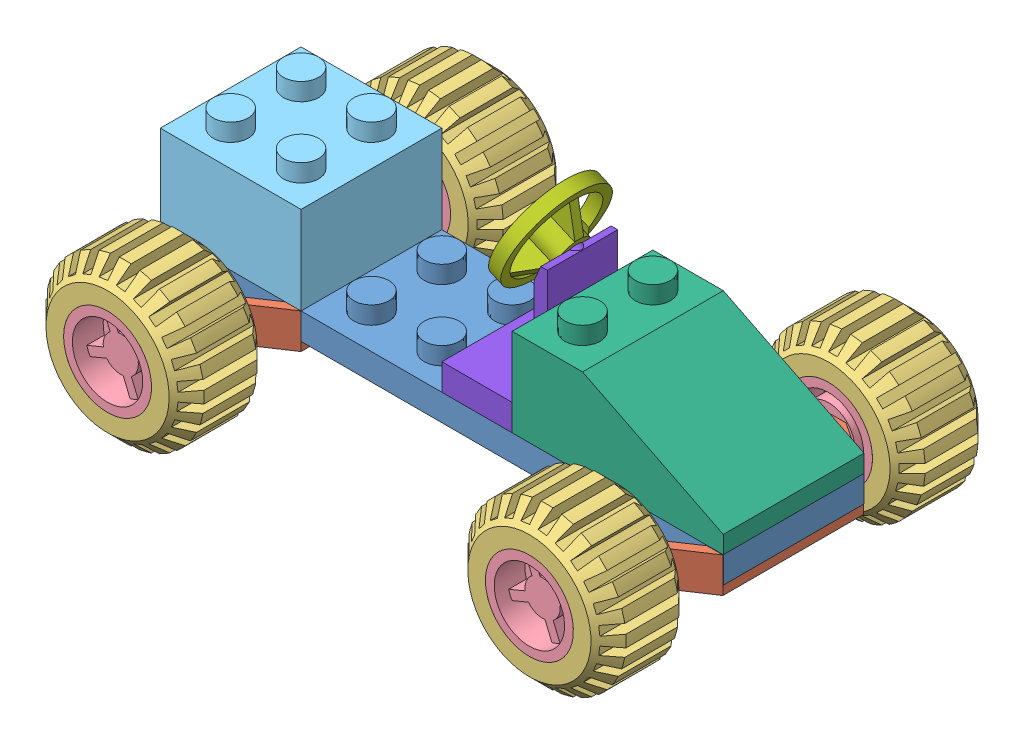
SolidWorks assembly Assem1, configuration Default. Lengths in mm.
Overall size (71.49 35.22 44.04).
21 component instances, 9 part files, 22 mates.
Components (placement in the parent):
- Bottom brick-1: Bottom brick [Default] at (14.6536 29.1359 55.1967) size (64 5 16)
- Chassis-1: Chassis [Default] at (38.6536 28.1359 55.2377) x (0 0 1) z (-1 0 0) size (40 4 16)
- Tire assembly-3: Tire assembly [klein] at (26.6106 15.8435 25.5957) size (17.97 17.97 10)
  - Tire-1: Tire [Default] at (12.043 14.2925 7.6421) size (17.97 17.97 10)
  - Wheel-1: Wheel [Default] at (12.043 14.2925 12.6421) size (10 10 10)
- Back brick-1: Back brick [Default] at (-17.3464 32.1359 47.1967) size (16 12 16)
- Chassis-3: Chassis [Default] at (-9.3464 28.1359 55.1967) x (0 0 1) z (-1 0 0) size (40 4 16)
- Tire assembly-6: Tire assembly [klein] at (-21.3894 15.8435 25.5547) size (17.97 17.97 10)
  - Tire-1: Tire [Default] at (12.043 14.2925 7.6421) size (17.97 17.97 10)
  - Wheel-1: Wheel [Default] at (12.043 14.2925 12.6421) size (10 10 10)
- Tire assembly-7: Tire assembly [klein] at (7.2528 21.5466 84.8388) x (-0.923728 -0.383049 0) z (0 0 -1) size (17.97 17.97 10)
  - Tire-1: Tire [Default] at (12.043 14.2925 7.6421) size (17.97 17.97 10)
  - Wheel-1: Wheel [Default] at (12.043 14.2925 12.6421) size (10 10 10)
- Tire assembly-8: Tire assembly [klein] at (55.2528 21.5466 84.8798) x (-0.923728 -0.383049 0) z (0 0 -1) size (17.97 17.97 10)
  - Tire-1: Tire [Default] at (12.043 14.2925 7.6421) size (17.97 17.97 10)
  - Wheel-1: Wheel [Default] at (12.043 14.2925 12.6421) size (10 10 10)
- Front brick-1: Front brick [Default] at (67.506 47.2492 63.1967) x (0 0 -1) z (1 0 0) size (16 12 24)
- Steering wheel assembly-1: Steering wheel assembly [Default] at (25.4459 35.2689 49.8892) x (0 0 1) z (-0.916157 0.400819 0) size (16 20.7 13.6)
  - Steering wheel-1: Steering wheel [Default] at (5.3075 7.6005 7.601) size (11.8 11.8 3.5)
  - Part7^Steering wheel assembly-1: Part7^Steering wheel assembly [Default] at origin (virtual)
  - Steering base-1: Steering base [Default] at (5.3075 -5.5928 4.9671) x (1 0 0) z (0 -0.400819 0.916157) size (16 15.65 8)
Mates (geometry in assembly coordinates):
- Coincident3: coincident anti-aligned: plane of Bottom brick-1 through (14.6536 29.1359 55.1967) normal (0 -1 0); plane of Chassis-1 through (38.6536 29.1359 55.2377) normal (0 1 0)
- Coincident4: coincident: plane of Bottom brick-1 through (46.6536 32.1359 47.1967) normal (1 0 0); line of Chassis-1 through (46.6536 28.1359 63.2377) axis (0 0 -1)
- Concentric3: concentric aligned: cylinder of Chassis-1 through (38.6536 30.1359 35.2377) axis (0 0 1) radius 1.5; cylinder of Tire assembly-3/Wheel-1 through (38.6536 30.1359 40.2377) axis (0 0 1) radius 1.5
- Coincident5: coincident anti-aligned: plane of Chassis-1 through (36.6536 29.1359 43.2377) normal (0 0 -1); plane of Tire assembly-3/Wheel-1 through (38.6536 30.1359 43.2377) normal (0 0 1)
- Coincident7: coincident anti-aligned: plane of Bottom brick-1 through (14.6536 32.1359 55.1967) normal (0 1 0); plane of Back brick-1 through (-17.3464 32.1359 47.1967) normal (0 -1 0)
- Coincident15: coincident aligned: plane of Bottom brick-1 through (-17.3464 32.1359 63.1967) normal (0 0 1); plane of Back brick-1 through (-17.3464 42.1359 63.1967) normal (0 0 1)
- Coincident16: coincident aligned: plane of Bottom brick-1 through (-17.3464 32.1359 47.1967) normal (-1 0 0); plane of Back brick-1 through (-17.3464 42.1359 47.1967) normal (-1 0 0)
- Coincident21: coincident anti-aligned: plane of Bottom brick-1 through (14.6536 29.1359 55.1967) normal (0 -1 0); plane of Chassis-3 through (-9.3464 29.1359 55.1967) normal (0 1 0)
- Coincident23: coincident aligned: plane of Bottom brick-1 through (-17.3464 32.1359 47.1967) normal (-1 0 0); plane of Chassis-3 through (-17.3464 29.1359 55.1967) normal (-1 0 0)
- Coincident25: coincident aligned: line of Bottom brick-1 through (-17.3464 32.1359 63.1967) axis (0 -1 0); line of Chassis-3 through (-17.3464 29.1359 63.1967) axis (0 -1 0)
- Concentric5: concentric aligned: cylinder of Chassis-3 through (-9.3464 30.1359 35.1967) axis (0 0 1) radius 1.5; cylinder of Tire assembly-6/Wheel-1 through (-9.3464 30.1359 40.1967) axis (0 0 1) radius 1.5
- Coincident26: coincident anti-aligned: plane of Chassis-3 through (-11.3464 29.1359 43.1967) normal (0 0 -1); plane of Tire assembly-6/Wheel-1 through (-9.3464 30.1359 43.1967) normal (0 0 1)
- Concentric6: concentric aligned: cylinder of Chassis-3 through (-9.3464 30.1359 75.1967) axis (0 0 -1) radius 1.5; cylinder of Tire assembly-7/Wheel-1 through (-9.3464 30.1359 70.1967) axis (0 0 -1) radius 1.5
- Coincident28: coincident anti-aligned: plane of Chassis-3 through (-11.3464 29.1359 67.1967) normal (0 0 1); plane of Tire assembly-7/Wheel-1 through (-9.3464 30.1359 67.1967) normal (0 0 -1)
- Concentric7: concentric aligned: cylinder of Chassis-1 through (38.6536 30.1359 75.2377) axis (0 0 -1) radius 1.5; cylinder of Tire assembly-8/Wheel-1 through (38.6536 30.1359 70.2377) axis (0 0 -1) radius 1.5
- Coincident29: coincident anti-aligned: plane of Chassis-1 through (36.6536 29.1359 67.2377) normal (0 0 1); circle of Tire assembly-8/Wheel-1
- Coincident30: coincident anti-aligned: plane of Bottom brick-1 through (14.6536 32.1359 55.1967) normal (0 1 0); plane of Front brick-1 through (46.6536 32.1359 47.1967) normal (0 -1 0)
- Coincident32: coincident aligned: plane of Bottom brick-1 through (46.6536 32.1359 47.1967) normal (1 0 0); plane of Front brick-1 through (46.6536 34.1359 47.1967) normal (1 0 0)
- Coincident33: coincident: line of Bottom brick-1 through (-17.3464 29.1359 63.1967) axis (1 0 0); plane of Front brick-1 through (67.506 47.2492 63.1967) normal (0 0 1)
- Coincident34: coincident: plane of Bottom brick-1 through (14.6536 32.1359 55.1967) normal (0 1 0); plane of Steering wheel assembly-1/Steering base-1 through (18.6536 32.1359 55.1967) normal (0 -1 0)
- Coincident36: coincident: plane of Bottom brick-1 through (-17.3464 32.1359 47.1967) normal (0 0 -1); plane of Steering wheel assembly-1/Steering base-1 through (22.6536 35.1359 47.1967) normal (0 0 -1)
- Coincident37: coincident anti-aligned: plane of Front brick-1 through (22.6536 32.1359 47.1967) normal (-1 0 0); plane of Steering wheel assembly-1/Steering base-1 through (22.6536 35.1359 47.1967) normal (1 0 0)
